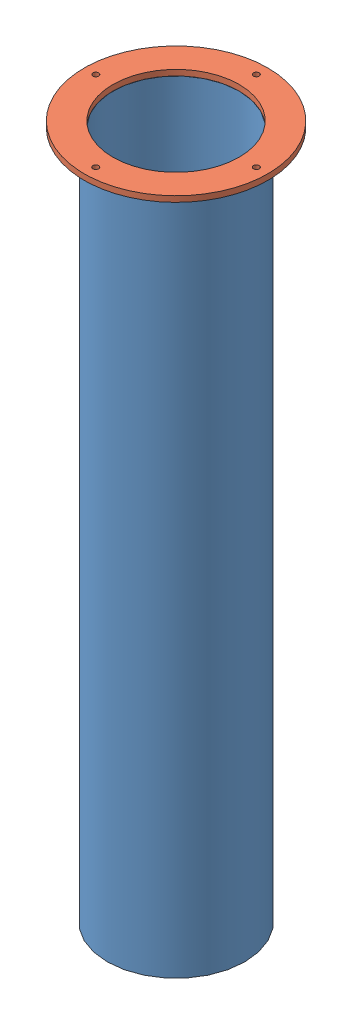
SolidWorks assembly middle shaft assembly, configuration Default. Lengths in mm.
Overall size (203.2 768.35 203.2).
2 component instances, 2 part files, 2 mates.
Components (placement in the parent):
- Middle Shaft-1: Middle Shaft [Default] at (-93.161 -254.9453 222.3658) size (152.4 762 152.4)
- middle shaft plate-1: middle shaft plate [Default] at (-93.161 507.0547 222.3658) size (203.2 6.35 203.2)
Mates (geometry in assembly coordinates):
- Concentric1: concentric: cylinder of Middle Shaft-1 through (-93.161 507.0547 222.3658) axis (0 -1 0) radius 69.85; circle of middle shaft plate-1
- Coincident2: coincident anti-aligned: plane of Middle Shaft-1 through (-93.161 507.0547 222.3658) normal (0 1 0); plane of middle shaft plate-1 through (-93.161 507.0547 222.3658) normal (0 -1 0)
